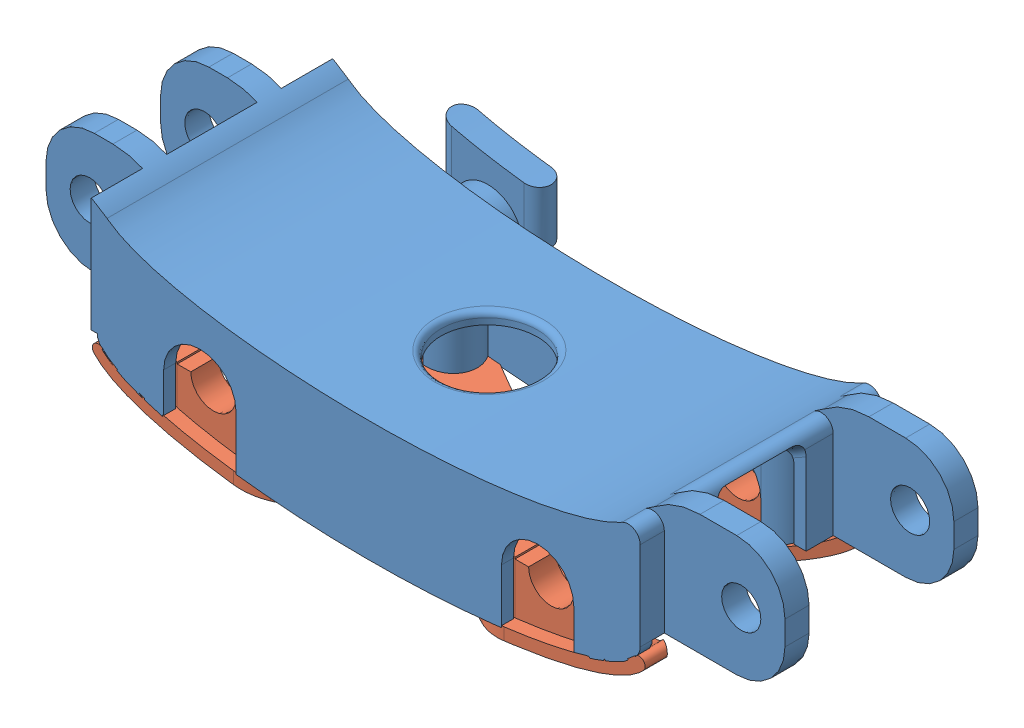
SolidWorks assembly Ensamblaje1, configuration Predeterminado. Lengths in mm.
Overall size (127 38.79 52.25).
2 component instances, 2 part files, 3 mates.
Components (placement in the parent):
- Soporte IR_10-1: Soporte IR_10 [Predeterminado] at (-10.4924 -4.2262 127) size (127 32.2 52.25)
- tapaSoporte IR_10-1: tapaSoporte IR_10 [Predeterminado] at (-10.4924 -3.9497 127) size (91.65 19.07 40)
Mates (geometry in assembly coordinates):
- Concéntrica3: concentric: cylinder of Soporte IR_10-1 through (11.5076 15.7748 162.5) axis (0 -1 0) radius 2.5; cylinder of tapaSoporte IR_10-1 through (11.5076 -16.1499 162.5) axis (0 1 0) radius 2.25
- Paralelo4: parallel: plane of Soporte IR_10-1 through (-10.4924 15.7748 114.75) normal (0 0 -1); plane of tapaSoporte IR_10-1 through (-44.4924 -16.1499 129.25) normal (0 0 -1)
- Coincidente2: coincident: plane of Soporte IR_10-1 through (-10.4924 -4.2262 127) normal (0 -1 0); plane of tapaSoporte IR_10-1 through (-10.4924 -4.2262 167.001) normal (0 1 0)
